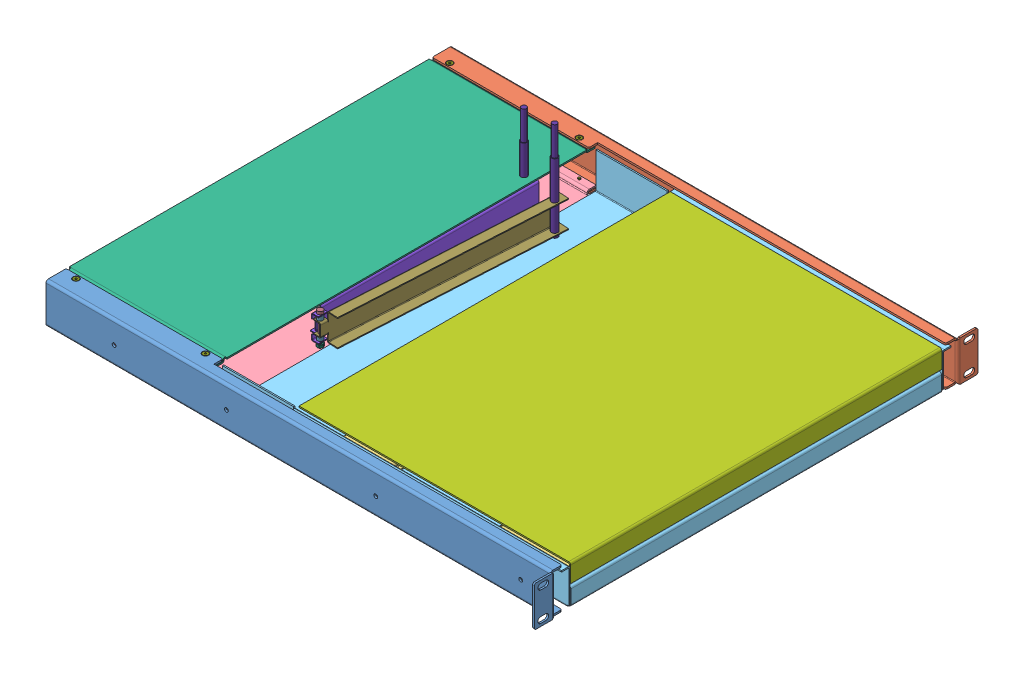
SolidWorks assembly KVM, configuration Valor predeterminado. Lengths in mm.
Overall size (599.42 141.99 489.8).
44 component instances, 17 part files, 84 mates.
Components (placement in the parent):
- 0301_RD_SW_PC_LATERAL_ESQUERDA-1: 0301_RD_SW_PC_LATERAL_ESQUERDA [Valor predeterminado] at (-31.8602 11.8791 560.93) size (560.01 44.45 42.85)
- 0301_RD_SW_PC_LATERAL_DIREITA-1: 0301_RD_SW_PC_LATERAL_DIREITA [Valor predeterminado] at (-31.8602 11.8791 112.13) x (1 0 0) z (0 0 -1) size (560.01 44.45 42.85)
- 0301_RD_SW_PC_SUPORTE_TECLADO-1: 0301_RD_SW_PC_SUPORTE_TECLADO [Valor predeterminado] at (193.8398 11.1541 339.755) x (0 0 -1) z (1 0 0) size (404.56 18 259.6)
- 0301_RD_SW_PC_00001-1: 0301_RD_SW_PC_00001 [Valor predeterminado] at (-136.3602 -10.3459 126.5301) x (0 0 1) z (1 0 0) size (420 42.7 175.5)
- 0301_RD_SW_PCBASE_TECLADO-2: 0301_RD_SW_PCBASE_TECLADO [Valor predeterminado] at (248.1398 -6.8459 542.0301) x (0 0 -1) z (1 0 0) size (429.9 40.76 382.6)
- 0301_RD_SW_PC_00002-1: 0301_RD_SW_PC_00002 [Valor predeterminado] at (-137.8602 34.1041 546.53) x (0 0 -1) z (1 0 0) size (420 5 174)
- 0301_RD_SW_PC_00004-1: 0301_RD_SW_PC_00004 [Valor predeterminado] at (248.1398 32.6041 541.53) x (-1 0 0) z (0 0 1) size (300 20 410)
- 0301_RD_SW_PC_00005-2: 0301_RD_SW_PC_00005 [Valor predeterminado] at (-143.2742 -3.1209 436.5454) x (0 1 0) z (-0.002767 0 0.999996) size (30 19 250)
- HDL 15-SL-B-1: HDL 15-SL-B [По умолчанию] at (-310.3602 14.6541 499.6556) x (0 0 -1) z (1 0 0) size (30.8 16.47 22.2)
- HDL 15-SL-B-2: HDL 15-SL-B [По умолчанию] at (-310.3602 14.6541 464.6556) x (0 0 -1) z (1 0 0) size (30.8 16.47 22.2)
- HDL 15-SL-B-3: HDL 15-SL-B [По умолчанию] at (-310.3602 14.6541 429.6556) x (0 0 -1) z (1 0 0) size (30.8 16.47 22.2)
- HDL 15-SL-B-4: HDL 15-SL-B [По умолчанию] at (-310.3602 14.6541 394.6556) x (0 0 -1) z (1 0 0) size (30.8 16.47 22.2)
- HDL 15-SL-B-5: HDL 15-SL-B [По умолчанию] at (-310.3602 14.6541 359.6556) x (0 0 -1) z (1 0 0) size (30.8 16.47 22.2)
- HDL 15-SL-B-6: HDL 15-SL-B [По умолчанию] at (-310.3602 14.6541 324.6556) x (0 0 -1) z (1 0 0) size (30.8 16.47 22.2)
- HDL 15-SL-B-7: HDL 15-SL-B [По умолчанию] at (-310.3602 14.6541 289.6556) x (0 0 -1) z (1 0 0) size (30.8 16.47 22.2)
- HDL 15-SL-B-8: HDL 15-SL-B [По умолчанию] at (-310.3602 14.6541 254.6556) x (0 0 -1) z (1 0 0) size (30.8 16.47 22.2)
- Power Jack_BODY-1: Power Jack_BODY [Valor predeterminado] at (-310.3602 8.1541 154.1826) x (0 0 1) z (-1 0 0) size (9.6 11.07 18.88)
- PS2 Connector Green-3: PS2 Connector Green [Valor predeterminado] at (-305.4114 14.6541 219.1556) x (0 0 -1) z (1 0 0) size (108.98 108.98 108.98)
- PS2 Connector Green-4: PS2 Connector Green [Valor predeterminado] at (-305.4114 14.6541 194.1556) x (0 0 -1) z (1 0 0) size (108.98 108.98 108.98)
- 0301_RD_SW_PC_00012-1: 0301_RD_SW_PC_00012 [Valor predeterminado] at (-133.7553 26.8791 435.8251) x (0 -1 0) z (-0.055984 0 0.998432) size (30 19 250)
- 0301_RD_SW_PC_00013-1: 0301_RD_SW_PC_00013 [Valor predeterminado] at (-138.3921 -6.8575 431.5589) x (-0.751495 0 0.659739) z (0 1 0) size (6 6 35)
- 0301_RD_SW_PC_00014-1: 0301_RD_SW_PC_00014 [Valor predeterminado] at (-138.3921 -0.3843 431.5589) x (0.840844 0 -0.541277) z (0 1 0) size (6 6 5)
- 0301_RD_SW_PC_00014-2: 0301_RD_SW_PC_00014 [Valor predeterminado] at (-138.3921 19.1425 431.5589) x (0.840844 0 -0.541277) z (0 1 0) size (6 6 5)
- PORCA COMUM DIN 934-1: PORCA COMUM DIN 934 [M03 DIN 934] at (-138.3921 -3.6575 431.5589) x (1 0 0) z (0 -1 0) size (6.93 6 3.2)
- PARAFUSO ALLEN CÔNICO DIN 7991-1: PARAFUSO ALLEN CÔNICO DIN 7991 [M3x06] at (-296.7002 28.1041 542.9301) x (0 1 0) z (0.756028 0 -0.654539) size (6 6 6)
- PARAFUSO ALLEN CÔNICO DIN 7991-2: PARAFUSO ALLEN CÔNICO DIN 7991 [M3x06] at (-153.7002 28.1041 542.9301) x (0 1 0) z (-0.756028 0 0.654539) size (6 6 6)
- PARAFUSO ALLEN CÔNICO DIN 7991-3: PARAFUSO ALLEN CÔNICO DIN 7991 [M3x06] at (6.7465 -2.3459 536.8367) x (0 -1 0) z (0.274927 0 0.961465) size (6 6 6)
- PARAFUSO ALLEN CÔNICO DIN 7991-4: PARAFUSO ALLEN CÔNICO DIN 7991 [M3x06] at (91.0715 -2.3459 536.8367) x (0 -1 0) z (-0.274927 0 -0.961465) size (6 6 6)
- PARAFUSO ALLEN CÔNICO DIN 7991-5: PARAFUSO ALLEN CÔNICO DIN 7991 [M3x05] at (192.8715 -3.3459 536.8367) x (0 -1 0) z (0.274927 0 0.961465) size (5 6 6)
- PARAFUSO ALLEN CÔNICO DIN 7991-6: PARAFUSO ALLEN CÔNICO DIN 7991 [M3x06] at (230.5674 -2.3459 509.755) x (0 -1 0) z (0.274927 0 0.961465) size (6 6 6)
- PARAFUSO ALLEN CÔNICO DIN 7991-7: PARAFUSO ALLEN CÔNICO DIN 7991 [M3x06] at (230.5674 -2.3459 409.755) x (0 -1 0) z (0.274927 0 0.961465) size (6 6 6)
- PARAFUSO ALLEN CÔNICO DIN 7991-8: PARAFUSO ALLEN CÔNICO DIN 7991 [M3x06] at (230.5674 -2.3459 269.755) x (0 -1 0) z (0.274927 0 0.961465) size (6 6 6)
- PARAFUSO ALLEN CÔNICO DIN 7991-9: PARAFUSO ALLEN CÔNICO DIN 7991 [M3x06] at (230.5674 -2.3459 169.755) x (0 -1 0) z (0.274927 0 0.961465) size (6 6 6)
- PARAFUSO ALLEN CÔNICO DIN 7991-10: PARAFUSO ALLEN CÔNICO DIN 7991 [M3x06] at (192.8715 -2.3459 142.6683) x (0 -1 0) z (0.274927 0 0.961465) size (6 6 6)
- PARAFUSO ALLEN CÔNICO DIN 7991-11: PARAFUSO ALLEN CÔNICO DIN 7991 [M3x06] at (91.0715 -2.3459 142.6683) x (0 -1 0) z (0.274927 0 0.961465) size (6 6 6)
- PARAFUSO ALLEN CÔNICO DIN 7991-12: PARAFUSO ALLEN CÔNICO DIN 7991 [M3x06] at (6.7465 -2.3459 142.6683) x (0 -1 0) z (0.274927 0 0.961465) size (6 6 6)
- PARAFUSO ALLEN CÔNICO DIN 7991-13: PARAFUSO ALLEN CÔNICO DIN 7991 [M3x06] at (-153.7002 -4.3459 130.13) x (0 -1 0) z (0.274927 0 0.961465) size (6 6 6)
- PARAFUSO ALLEN CÔNICO DIN 7991-14: PARAFUSO ALLEN CÔNICO DIN 7991 [M3x06] at (-296.7002 -4.3459 130.13) x (0 -1 0) z (0.274927 0 0.961465) size (6 6 6)
- PARAFUSO ALLEN CÔNICO DIN 7991-15: PARAFUSO ALLEN CÔNICO DIN 7991 [M3x06] at (-296.7002 -4.3459 542.9301) x (0 -1 0) z (0.274927 0 0.961465) size (6 6 6)
- PARAFUSO ALLEN CÔNICO DIN 7991-16: PARAFUSO ALLEN CÔNICO DIN 7991 [M3x06] at (-153.7002 -4.3459 542.9301) x (0 -1 0) z (0.274927 0 0.961465) size (6 6 6)
- PARAFUSO ALLEN CÔNICO DIN 7991-17: PARAFUSO ALLEN CÔNICO DIN 7991 [M3x06] at (-153.7002 28.1041 130.13) x (0 1 0) z (-0.756028 0 0.654539) size (6 6 6)
- PARAFUSO ALLEN CÔNICO DIN 7991-18: PARAFUSO ALLEN CÔNICO DIN 7991 [M3x06] at (-296.7002 28.1041 130.13) x (0 1 0) z (-0.756028 0 0.654539) size (6 6 6)
- 0301_RD_SW_PC_00015-1: 0301_RD_SW_PC_00015 [Valor predeterminado] at (-148.4785 99.1541 196.5301) x (-0.045253 0 0.998976) z (0 -1 0) size (7 7 108)
- 0301_RD_SW_PC_00015-2: 0301_RD_SW_PC_00015 [Valor predeterminado] at (-114.4602 101.1541 196.5301) x (-0.891391 0 -0.453234) z (0 -1 0) size (7 7 108)
Mates (geometry in assembly coordinates):
- Coincidente1: coincident aligned: plane of 0301_RD_SW_PC_LATERAL_ESQUERDA-1 through (248.1398 11.8791 560.93) normal (1 0 0); plane of 0301_RD_SW_PC_LATERAL_DIREITA-1 through (248.1398 11.8791 112.13) normal (1 0 0)
- Coincidente2: coincident aligned: plane of 0301_RD_SW_PC_LATERAL_ESQUERDA-1 through (-31.8602 34.1041 560.93) normal (0 1 0); plane of 0301_RD_SW_PC_LATERAL_DIREITA-1 through (-31.8602 34.1041 112.13) normal (0 1 0)
- Distância1: distance = 465 mm: line of 0301_RD_SW_PC_LATERAL_ESQUERDA-1 through (248.1398 24.5791 569.03) axis (-1 0 0); line of 0301_RD_SW_PC_LATERAL_DIREITA-1 through (246.1398 24.5791 104.0301) axis (1 0 0)
- Coincidente7: coincident anti-aligned: plane of 0301_RD_SW_PC_SUPORTE_TECLADO-1 through (193.8398 11.1541 542.0301) normal (0 0 1); plane of 0301_RD_SW_PCBASE_TECLADO-2 through (248.1398 -6.8459 542.0301) normal (0 0 -1)
- Coincidente8: coincident anti-aligned: plane of 0301_RD_SW_PC_SUPORTE_TECLADO-1 through (193.8398 -6.8459 339.755) normal (0 -1 0); plane of 0301_RD_SW_PCBASE_TECLADO-2 through (248.1398 -6.8459 542.0301) normal (0 1 0)
- Coincidente9: coincident anti-aligned: plane of 0301_RD_SW_PC_SUPORTE_TECLADO-1 through (237.1398 11.1541 339.755) normal (1 0 0); plane of 0301_RD_SW_PCBASE_TECLADO-2 through (237.1398 11.2041 131.7667) normal (-1 0 0)
- Coincidente10: coincident anti-aligned: plane of 0301_RD_SW_PC_LATERAL_ESQUERDA-1 through (-31.8602 -8.3459 560.93) normal (0 1 0); plane of 0301_RD_SW_PCBASE_TECLADO-2 through (248.1398 -8.3459 542.0301) normal (0 -1 0)
- Paralelo2: parallel anti-aligned: plane of 0301_RD_SW_PC_LATERAL_ESQUERDA-1 through (-31.8602 11.8791 558.93) normal (0 0 -1); plane of 0301_RD_SW_PCBASE_TECLADO-2 through (248.1398 -6.8459 543.53) normal (0 0 1)
- Largura1: width aligned: plane of 0301_RD_SW_PCBASE_TECLADO-2 through (248.1398 -6.8459 543.53) normal (0 0 1); plane of 0301_RD_SW_PCBASE_TECLADO-2 through (248.1398 -6.8459 129.5301) normal (0 0 -1); plane of 0301_RD_SW_PC_LATERAL_DIREITA-1 through (-31.8602 11.8791 114.13) normal (0 0 1); plane of 0301_RD_SW_PC_LATERAL_ESQUERDA-1 through (-31.8602 11.8791 558.93) normal (0 0 -1)
- Coincidente12: coincident aligned: plane of 0301_RD_SW_PC_LATERAL_DIREITA-1 through (-311.8602 -10.3459 124.6301) normal (-1 0 0); plane of 0301_RD_SW_PC_00001-1 through (-311.8602 -10.3459 126.5301) normal (-1 0 0)
- Coincidente13: coincident aligned: plane of 0301_RD_SW_PC_LATERAL_ESQUERDA-1 through (-31.8602 -10.3459 560.93) normal (0 -1 0); plane of 0301_RD_SW_PC_00001-1 through (-136.3602 -10.3459 126.5301) normal (0 -1 0)
- Largura2: width aligned: plane of 0301_RD_SW_PC_00001-1 through (-311.8602 32.3541 137.9045) normal (0 0 -1); plane of 0301_RD_SW_PC_00001-1 through (-311.8602 -8.8459 535.1556) normal (0 0 1); plane of 0301_RD_SW_PC_LATERAL_ESQUERDA-1 through (-31.8602 11.8791 558.93) normal (0 0 -1); plane of 0301_RD_SW_PC_LATERAL_DIREITA-1 through (-31.8602 11.8791 114.13) normal (0 0 1)
- Coincidente14: coincident aligned: plane of 0301_RD_SW_PC_LATERAL_DIREITA-1 through (-31.8602 34.1041 112.13) normal (0 1 0); plane of 0301_RD_SW_PC_00002-1 through (-137.8602 34.1041 546.53) normal (0 1 0)
- Coincidente15: coincident aligned: plane of 0301_RD_SW_PC_00001-1 through (-311.8602 -10.3459 126.5301) normal (-1 0 0); plane of 0301_RD_SW_PC_00002-1 through (-311.8602 32.6041 546.53) normal (-1 0 0)
- Largura3: width aligned: plane of 0301_RD_SW_PC_00002-1 through (-311.8602 29.1031 137.9045) normal (0 0 -1); plane of 0301_RD_SW_PC_00002-1 through (-311.8602 29.1031 535.1556) normal (0 0 1); plane of 0301_RD_SW_PC_LATERAL_ESQUERDA-1 through (-31.8602 11.8791 558.93) normal (0 0 -1); plane of 0301_RD_SW_PC_LATERAL_DIREITA-1 through (-31.8602 11.8791 114.13) normal (0 0 1)
- DistânciaLimite1: limit distance = 0 mm aligned: plane of 0301_RD_SW_PC_LATERAL_ESQUERDA-1 through (248.1398 11.8791 560.93) normal (1 0 0); plane of 0301_RD_SW_PCBASE_TECLADO-2 through (248.1398 -6.8459 542.0301) normal (1 0 0)
- Coincidente18: coincident aligned: plane of 0301_RD_SW_PC_00002-1 through (-137.8602 34.1041 546.53) normal (0 1 0); plane of 0301_RD_SW_PC_00004-1 through (248.1398 34.1041 541.53) normal (0 1 0)
- Largura6: width aligned: plane of 0301_RD_SW_PCBASE_TECLADO-2 through (248.1398 -6.8459 542.0301) normal (0 0 -1); plane of 0301_RD_SW_PCBASE_TECLADO-2 through (248.1398 -6.8459 131.0301) normal (0 0 1); plane of 0301_RD_SW_PC_00004-1 through (248.1398 32.6041 131.5301) normal (0 0 -1); plane of 0301_RD_SW_PC_00004-1 through (248.1398 14.1041 541.53) normal (0 0 1)
- Coincidente19: coincident aligned: plane of 0301_RD_SW_PCBASE_TECLADO-2 through (248.1398 -6.8459 542.0301) normal (1 0 0); plane of 0301_RD_SW_PC_00004-1 through (248.1398 32.6041 541.53) normal (1 0 0)
- Concêntrico6: concentric aligned: cylinder of 0301_RD_SW_PC_00002-1 through (-148.4785 34.1041 196.5301) axis (0 1 0) radius 1.7; cylinder of 0301_RD_SW_PC_00005-2 through (-148.4785 26.8791 196.5301) axis (0 1 0) radius 2.75
- Coincidente25: coincident anti-aligned: plane of 0301_RD_SW_PC_00001-1 through (-310.3602 -10.3459 126.5301) normal (1 0 0); plane of HDL 15-SL-B-1 through (-310.3602 9.8791 485.7556) normal (-1 0 0)
- Distância4: distance = 17 mm anti-aligned: plane of Power Jack_BODY-1 through (-309.8602 8.1541 150.1826) normal (0 -1 0); plane of 0301_RD_SW_PC_00001-1 through (-136.3602 -8.8459 126.5301) normal (0 1 0)
- Largura9: width anti-aligned: plane of ? through (-301.8602 12.1541 484.1556) normal (0 1 0); plane of ? through (-301.8602 17.1541 484.1556) normal (0 -1 0); cylinder of HDL 15-SL-B-1 through (-294.0602 14.6541 487.1556) axis (-1 0 0) radius 1.5
- Paralelo7: parallel anti-aligned: plane of 0301_RD_SW_PC_00001-1 through (-301.8602 9.6541 490.1556) normal (0 1 0); plane of HDL 15-SL-B-1 through (-316.2602 10.8847 493.4888) normal (0 -1 0)
- Largura10: width anti-aligned: plane of ? through (-301.8602 17.1541 515.1556) normal (0 0 -1); plane of ? through (-301.8602 17.1541 484.1556) normal (0 0 1); cylinder of HDL 15-SL-B-1 through (-300.0602 16.8247 499.6556) axis (-1 0 0) radius 0.635
- Coincidente37: coincident aligned: plane of 0301_RD_SW_PC_00001-1 through (-311.8602 -10.3459 126.5301) normal (-1 0 0); plane of PS2 Connector Green-3 through (-311.8602 9.7344 214.2358) normal (-1 0 0)
- Concêntrico7: concentric anti-aligned: cylinder of 0301_RD_SW_PC_00001-1 through (-136.3602 14.6541 219.1556) axis (-1 0 0) radius 5.5; cylinder of PS2 Connector Green-3 through (-312.5051 14.6541 219.1556) axis (1 0 0) radius 4.8614
- Paralelo8: parallel aligned: plane of 0301_RD_SW_PC_00001-1 through (-136.3602 -8.8459 126.5301) normal (0 1 0); plane of PS2 Connector Green-3 through (-305.9074 12.273 219.9493) normal (0 1 0)
- Coincidente38: coincident aligned: plane of 0301_RD_SW_PC_00001-1 through (-311.8602 -10.3459 126.5301) normal (-1 0 0); plane of PS2 Connector Green-4 through (-311.8602 9.7344 189.2358) normal (-1 0 0)
- Concêntrico9: concentric anti-aligned: cylinder of 0301_RD_SW_PC_00001-1 through (-136.3602 14.6541 194.1556) axis (-1 0 0) radius 5.5; cylinder of PS2 Connector Green-4 through (-312.5051 14.6541 194.1556) axis (1 0 0) radius 4.8614
- Coincidente39: coincident aligned: plane of PS2 Connector Green-3 through (-305.9074 12.273 219.9493) normal (0 1 0); plane of PS2 Connector Green-4 through (-305.9074 12.273 194.9493) normal (0 1 0)
- Paralelo9: parallel aligned: plane of 0301_RD_SW_PC_00001-1 through (-301.8602 9.6541 245.1556) normal (0 1 0); plane of PS2 Connector Green-3 through (-305.9074 12.273 219.9493) normal (0 1 0)
- Coincidente41: coincident aligned: plane of 0301_RD_SW_PC_00005-2 through (-143.2742 26.8791 436.5454) normal (0 1 0); plane of 0301_RD_SW_PC_00012-1 through (-133.7553 26.8791 435.8251) normal (0 1 0)
- Concêntrico14: concentric anti-aligned: cylinder of 0301_RD_SW_PC_00005-2 through (-138.3921 -1.3843 431.5589) axis (0 -1 0) radius 1.7; cylinder of 0301_RD_SW_PC_00012-1 through (-138.3921 19.1425 431.5589) axis (0 1 0) radius 1.7
- Concêntrico15: concentric anti-aligned: cylinder of 0301_RD_SW_PCBASE_TECLADO-2 through (-114.4602 -6.8459 196.5301) axis (0 1 0) radius 1.6; cylinder of 0301_RD_SW_PC_00012-1 through (-114.4602 -3.1209 196.5301) axis (0 -1 0) radius 2.75
- Largura11: width aligned: plane of 0301_RD_SW_PC_00005-2 through (-143.2742 -3.1209 436.5454) normal (0 -1 0); plane of 0301_RD_SW_PC_00005-2 through (-143.2742 26.8791 436.5454) normal (0 1 0); plane of 0301_RD_SW_PC_00002-1 through (-137.8602 32.6041 546.53) normal (0 -1 0); plane of ? through (-136.3602 -8.8459 126.5301) normal (0 1 0)
- Coincidente43: coincident anti-aligned: plane of 0301_RD_SW_PC_00005-2 through (-143.2742 25.1425 436.5454) normal (0 1 0); plane of 0301_RD_SW_PC_00013-1 through (-138.3921 25.1425 431.5589) normal (0 -1 0)
- Concêntrico17: concentric aligned: cylinder of 0301_RD_SW_PC_00013-1 through (-138.3921 25.1425 431.5589) axis (0 -1 0) radius 1.7; cylinder of 0301_RD_SW_PC_00014-1 through (-138.3921 4.6157 431.5589) axis (0 -1 0) radius 1.725
- Coincidente44: coincident anti-aligned: plane of 0301_RD_SW_PC_00005-2 through (-143.2742 -0.3843 436.5454) normal (0 1 0); plane of 0301_RD_SW_PC_00014-1 through (-138.3921 -0.3843 431.5589) normal (0 -1 0)
- Concêntrico18: concentric aligned: cylinder of 0301_RD_SW_PC_00013-1 through (-138.3921 25.1425 431.5589) axis (0 -1 0) radius 1.7; cylinder of 0301_RD_SW_PC_00014-2 through (-138.3921 24.1425 431.5589) axis (0 -1 0) radius 1.725
- Coincidente45: coincident anti-aligned: plane of 0301_RD_SW_PC_00012-1 through (-133.7553 19.1425 435.8251) normal (0 1 0); plane of 0301_RD_SW_PC_00014-2 through (-138.3921 19.1425 431.5589) normal (0 -1 0)
- Concêntrico19: concentric aligned: cylinder of 0301_RD_SW_PC_00005-2 through (-138.3921 -1.3843 431.5589) axis (0 -1 0) radius 1.7; cylinder of 0301_RD_SW_PC_00013-1 through (-138.3921 25.1425 431.5589) axis (0 -1 0) radius 1.7
- Concêntrico20: concentric anti-aligned: cylinder of 0301_RD_SW_PC_00013-1 through (-138.3921 25.1425 431.5589) axis (0 -1 0) radius 1.7; cylinder of PORCA COMUM DIN 934-1 through (-138.3921 -6.8575 431.5589) axis (0 1 0) radius 1.5
- Coincidente46: coincident aligned: plane of 0301_RD_SW_PC_00013-1 through (-138.3921 -6.8575 431.5589) normal (0 -1 0); plane of PORCA COMUM DIN 934-1 through (-134.928 -6.8575 431.5589) normal (0 -1 0)
- Concêntrico21: concentric anti-aligned: cylinder of 0301_RD_SW_PC_00002-1 through (-296.7002 30.6041 542.9301) axis (0 1 0) radius 1.25; cylinder of PARAFUSO ALLEN CÔNICO DIN 7991-1 through (-296.7002 18.0008 542.9301) axis (0 -1 0) radius 1.25
- Coincidente47: coincident aligned: plane of 0301_RD_SW_PC_LATERAL_ESQUERDA-1 through (-31.8602 34.1041 560.93) normal (0 1 0); plane of PARAFUSO ALLEN CÔNICO DIN 7991-1 through (-294.7366 34.1041 545.1981) normal (0 1 0)
- Concêntrico22: concentric aligned: cone of 0301_RD_SW_PC_LATERAL_ESQUERDA-1 through (-153.7002 34.1041 542.9301) axis (0 -1 0); cylinder of PARAFUSO ALLEN CÔNICO DIN 7991-2 through (-153.7002 18.0008 542.9301) axis (0 -1 0) radius 1.25
- Coincidente48: coincident aligned: plane of 0301_RD_SW_PC_LATERAL_ESQUERDA-1 through (-31.8602 34.1041 560.93) normal (0 1 0); plane of PARAFUSO ALLEN CÔNICO DIN 7991-2 through (-155.6638 34.1041 540.662) normal (0 1 0)
- Concêntrico23: concentric aligned: cone of 0301_RD_SW_PCBASE_TECLADO-2 through (6.7465 -8.3459 536.8367) axis (0 1 0); cylinder of PARAFUSO ALLEN CÔNICO DIN 7991-3 through (6.7465 7.7575 536.8367) axis (0 1 0) radius 1.25
- Coincidente49: coincident aligned: plane of 0301_RD_SW_PCBASE_TECLADO-2 through (248.1398 -8.3459 542.0301) normal (0 -1 0); plane of PARAFUSO ALLEN CÔNICO DIN 7991-3 through (9.6309 -8.3459 536.012) normal (0 -1 0)
- Concêntrico24: concentric anti-aligned: circle of 0301_RD_SW_PCBASE_TECLADO-2; cylinder of PARAFUSO ALLEN CÔNICO DIN 7991-4 through (91.0715 7.7575 536.8367) axis (0 1 0) radius 1.25
- Coincidente50: coincident aligned: plane of 0301_RD_SW_PCBASE_TECLADO-2 through (248.1398 -8.3459 542.0301) normal (0 -1 0); plane of PARAFUSO ALLEN CÔNICO DIN 7991-4 through (88.1871 -8.3459 537.6615) normal (0 -1 0)
- Concêntrico25: concentric aligned: cone of 0301_RD_SW_PCBASE_TECLADO-2 through (192.8715 -8.3459 536.8367) axis (0 1 0); cylinder of PARAFUSO ALLEN CÔNICO DIN 7991-5 through (192.8715 6.7575 536.8367) axis (0 1 0) radius 1.25
- Coincidente51: coincident aligned: plane of 0301_RD_SW_PCBASE_TECLADO-2 through (248.1398 -8.3459 542.0301) normal (0 -1 0); plane of PARAFUSO ALLEN CÔNICO DIN 7991-5 through (195.7559 -8.3459 536.012) normal (0 -1 0)
- Concêntrico26: concentric aligned: cone of 0301_RD_SW_PCBASE_TECLADO-2 through (230.5674 -8.3459 509.755) axis (0 1 0); cylinder of PARAFUSO ALLEN CÔNICO DIN 7991-6 through (230.5674 7.7575 509.755) axis (0 1 0) radius 1.25
- Coincidente52: coincident aligned: plane of 0301_RD_SW_PCBASE_TECLADO-2 through (248.1398 -8.3459 542.0301) normal (0 -1 0); plane of PARAFUSO ALLEN CÔNICO DIN 7991-6 through (233.4518 -8.3459 508.9303) normal (0 -1 0)
- Concêntrico27: concentric aligned: cone of 0301_RD_SW_PCBASE_TECLADO-2 through (230.5674 -8.3459 409.755) axis (0 1 0); cylinder of PARAFUSO ALLEN CÔNICO DIN 7991-7 through (230.5674 7.7575 409.755) axis (0 1 0) radius 1.25
- Coincidente53: coincident aligned: plane of 0301_RD_SW_PCBASE_TECLADO-2 through (248.1398 -8.3459 542.0301) normal (0 -1 0); plane of PARAFUSO ALLEN CÔNICO DIN 7991-7 through (233.4518 -8.3459 408.9303) normal (0 -1 0)
- Concêntrico28: concentric aligned: cone of 0301_RD_SW_PCBASE_TECLADO-2 through (230.5674 -8.3459 269.755) axis (0 1 0); cylinder of PARAFUSO ALLEN CÔNICO DIN 7991-8 through (230.5674 7.7575 269.755) axis (0 1 0) radius 1.25
- Coincidente54: coincident aligned: plane of 0301_RD_SW_PCBASE_TECLADO-2 through (248.1398 -8.3459 542.0301) normal (0 -1 0); plane of PARAFUSO ALLEN CÔNICO DIN 7991-8 through (233.4518 -8.3459 268.9303) normal (0 -1 0)
- Concêntrico29: concentric aligned: cone of 0301_RD_SW_PCBASE_TECLADO-2 through (230.5674 -8.3459 169.755) axis (0 1 0); cylinder of PARAFUSO ALLEN CÔNICO DIN 7991-9 through (230.5674 7.7575 169.755) axis (0 1 0) radius 1.25
- Coincidente55: coincident aligned: plane of 0301_RD_SW_PCBASE_TECLADO-2 through (248.1398 -8.3459 542.0301) normal (0 -1 0); plane of PARAFUSO ALLEN CÔNICO DIN 7991-9 through (233.4518 -8.3459 168.9303) normal (0 -1 0)
- Concêntrico30: concentric aligned: cone of 0301_RD_SW_PCBASE_TECLADO-2 through (192.8715 -8.3459 142.6683) axis (0 1 0); cylinder of PARAFUSO ALLEN CÔNICO DIN 7991-10 through (192.8715 7.7575 142.6683) axis (0 1 0) radius 1.25
- Coincidente56: coincident aligned: plane of 0301_RD_SW_PCBASE_TECLADO-2 through (248.1398 -8.3459 542.0301) normal (0 -1 0); plane of PARAFUSO ALLEN CÔNICO DIN 7991-10 through (195.7559 -8.3459 141.8435) normal (0 -1 0)
- Concêntrico31: concentric aligned: cone of 0301_RD_SW_PCBASE_TECLADO-2 through (91.0715 -8.3459 142.6683) axis (0 1 0); cylinder of PARAFUSO ALLEN CÔNICO DIN 7991-11 through (91.0715 7.7575 142.6683) axis (0 1 0) radius 1.25
- Coincidente57: coincident aligned: plane of 0301_RD_SW_PCBASE_TECLADO-2 through (248.1398 -8.3459 542.0301) normal (0 -1 0); plane of PARAFUSO ALLEN CÔNICO DIN 7991-11 through (93.9559 -8.3459 141.8435) normal (0 -1 0)
- Concêntrico32: concentric aligned: cone of 0301_RD_SW_PCBASE_TECLADO-2 through (6.7465 -8.3459 142.6683) axis (0 1 0); cylinder of PARAFUSO ALLEN CÔNICO DIN 7991-12 through (6.7465 7.7575 142.6683) axis (0 1 0) radius 1.25
- Coincidente58: coincident aligned: plane of 0301_RD_SW_PCBASE_TECLADO-2 through (248.1398 -8.3459 542.0301) normal (0 -1 0); plane of PARAFUSO ALLEN CÔNICO DIN 7991-12 through (9.6309 -8.3459 141.8435) normal (0 -1 0)
- Concêntrico33: concentric aligned: cone of 0301_RD_SW_PC_LATERAL_DIREITA-1 through (-153.7002 -10.3459 130.13) axis (0 1 0); cylinder of PARAFUSO ALLEN CÔNICO DIN 7991-13 through (-153.7002 5.7575 130.13) axis (0 1 0) radius 1.25
- Coincidente59: coincident aligned: plane of 0301_RD_SW_PC_LATERAL_DIREITA-1 through (-31.8602 -10.3459 112.13) normal (0 -1 0); plane of PARAFUSO ALLEN CÔNICO DIN 7991-13 through (-150.8158 -10.3459 129.3053) normal (0 -1 0)
- Concêntrico34: concentric aligned: cone of 0301_RD_SW_PC_LATERAL_DIREITA-1 through (-296.7002 -10.3459 130.13) axis (0 1 0); cylinder of PARAFUSO ALLEN CÔNICO DIN 7991-14 through (-296.7002 5.7575 130.13) axis (0 1 0) radius 1.25
- Coincidente60: coincident aligned: plane of 0301_RD_SW_PC_LATERAL_DIREITA-1 through (-31.8602 -10.3459 112.13) normal (0 -1 0); plane of PARAFUSO ALLEN CÔNICO DIN 7991-14 through (-293.8158 -10.3459 129.3053) normal (0 -1 0)
- Concêntrico35: concentric aligned: cone of 0301_RD_SW_PC_LATERAL_ESQUERDA-1 through (-296.7002 -10.3459 542.9301) axis (0 1 0); cylinder of PARAFUSO ALLEN CÔNICO DIN 7991-15 through (-296.7002 5.7575 542.9301) axis (0 1 0) radius 1.25
- Coincidente61: coincident aligned: plane of 0301_RD_SW_PC_LATERAL_ESQUERDA-1 through (-31.8602 -10.3459 560.93) normal (0 -1 0); plane of PARAFUSO ALLEN CÔNICO DIN 7991-15 through (-293.8158 -10.3459 542.1053) normal (0 -1 0)
- Concêntrico36: concentric aligned: cone of 0301_RD_SW_PC_LATERAL_ESQUERDA-1 through (-153.7002 -10.3459 542.9301) axis (0 1 0); cylinder of PARAFUSO ALLEN CÔNICO DIN 7991-16 through (-153.7002 5.7575 542.9301) axis (0 1 0) radius 1.25
- Coincidente62: coincident aligned: plane of 0301_RD_SW_PC_LATERAL_ESQUERDA-1 through (-31.8602 -10.3459 560.93) normal (0 -1 0); plane of PARAFUSO ALLEN CÔNICO DIN 7991-16 through (-150.8158 -10.3459 542.1053) normal (0 -1 0)
- Concêntrico37: concentric aligned: cone of 0301_RD_SW_PC_LATERAL_DIREITA-1 through (-153.7002 34.1041 130.13) axis (0 -1 0); cylinder of PARAFUSO ALLEN CÔNICO DIN 7991-17 through (-153.7002 18.0008 130.13) axis (0 -1 0) radius 1.25
- Coincidente63: coincident aligned: plane of 0301_RD_SW_PC_LATERAL_DIREITA-1 through (-31.8602 34.1041 112.13) normal (0 1 0); plane of PARAFUSO ALLEN CÔNICO DIN 7991-17 through (-155.6638 34.1041 127.862) normal (0 1 0)
- Concêntrico38: concentric aligned: cone of 0301_RD_SW_PC_LATERAL_DIREITA-1 through (-296.7002 34.1041 130.13) axis (0 -1 0); cylinder of PARAFUSO ALLEN CÔNICO DIN 7991-18 through (-296.7002 18.0008 130.13) axis (0 -1 0) radius 1.25
- Coincidente64: coincident aligned: plane of 0301_RD_SW_PC_LATERAL_DIREITA-1 through (-31.8602 34.1041 112.13) normal (0 1 0); plane of PARAFUSO ALLEN CÔNICO DIN 7991-18 through (-298.6638 34.1041 127.862) normal (0 1 0)
- Concêntrico39: concentric aligned: cylinder of 0301_RD_SW_PC_00005-2 through (-148.4785 26.8791 196.5301) axis (0 1 0) radius 2.75; cylinder of 0301_RD_SW_PC_00015-1 through (-148.4785 67.1541 196.5301) axis (0 1 0) radius 2.75
- Coincidente65: coincident anti-aligned: plane of 0301_RD_SW_PC_00001-1 through (-136.3602 -8.8459 126.5301) normal (0 1 0); plane of 0301_RD_SW_PC_00015-1 through (-148.4785 -8.8459 196.5301) normal (0 -1 0)
- Coincidente66: coincident anti-aligned: plane of 0301_RD_SW_PCBASE_TECLADO-2 through (248.1398 -6.8459 542.0301) normal (0 1 0); plane of 0301_RD_SW_PC_00015-2 through (-114.4602 -6.8459 196.5301) normal (0 -1 0)
- Concêntrico40: concentric anti-aligned: cylinder of 0301_RD_SW_PC_00012-1 through (-114.4602 -3.1209 196.5301) axis (0 -1 0) radius 2.75; cylinder of 0301_RD_SW_PC_00015-2 through (-114.4602 69.1541 196.5301) axis (0 1 0) radius 2.75
